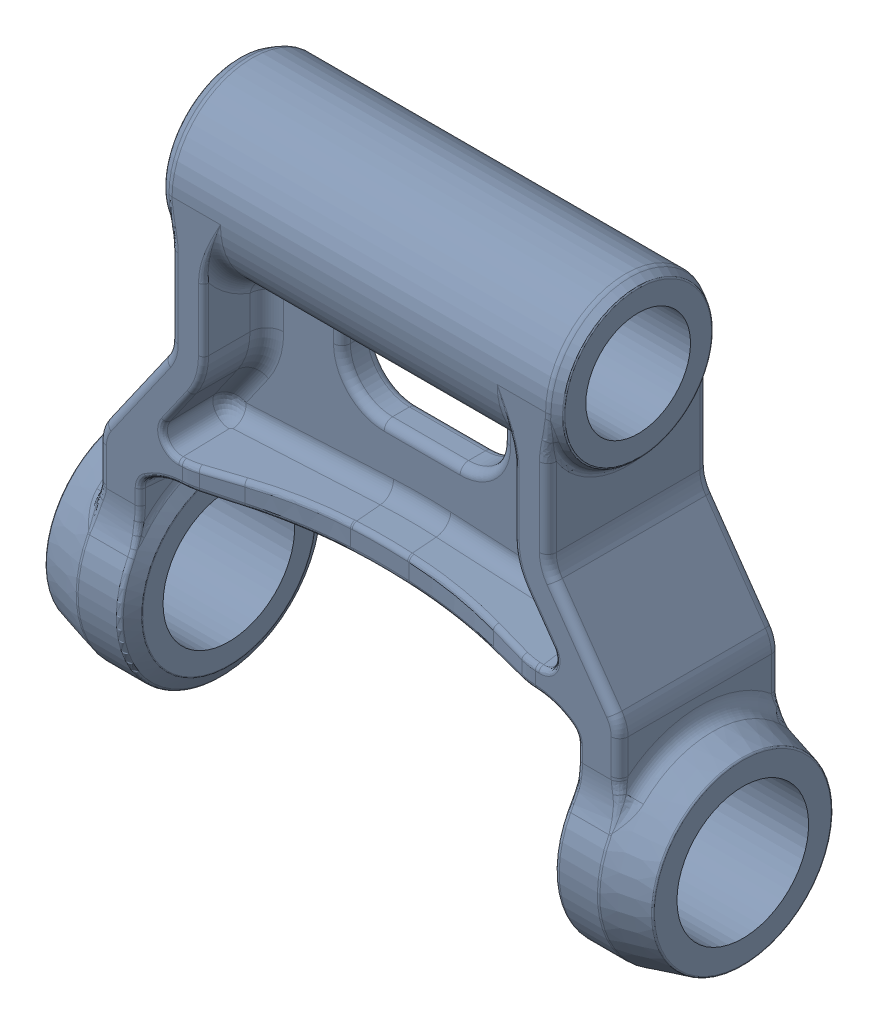
SolidWorks assembly 6344171, configuration Default. Lengths in mm.
Overall size (354 327.5 120).
2 component instances, 2 part files, 3 mates.
Components (placement in the parent):
- Dogbone H2I-1: Dogbone H2I [Default] at origin size (360 327.5 120)
- 6344171_sv-1: 6344171_sv [Default] x (0 0 -1) z (1 0 0) (suppressed, hidden)
Mates (geometry in assembly coordinates):
- Concentric1: concentric anti-aligned: cylinder of Dogbone H2I-1 through (0 0 0) axis (-1 0 0) radius 47.5; cylinder of assembly through (0 0 0) axis (1 0 0) radius 47.5
- Concentric2: concentric aligned: cylinder of Dogbone H2I-1 through (0 -220 0) axis (-1 0 0) radius 60; cylinder of assembly through (126.5 -220 0) axis (-1 0 0) radius 57.5
- Coincident1: coincident: plane of 6344171_sv-1; plane of assembly through (0 0 0) normal (1 0 0)
